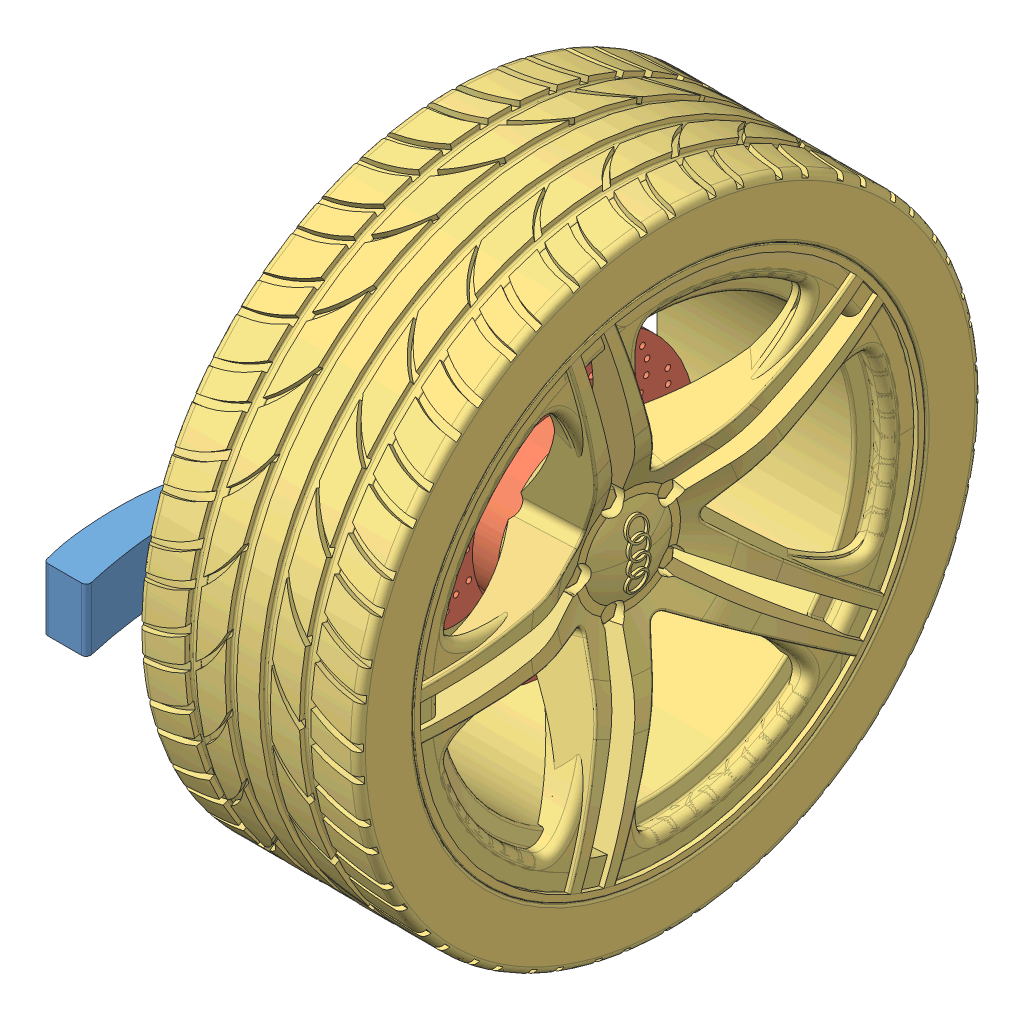
SolidWorks assembly Assem9, configuration Default. Lengths in mm.
Overall size (361.62 668.92 691.48).
3 component instances, 3 part files, 5 mates.
Components (placement in the parent):
- KHUNG TREO R-1: KHUNG TREO R [Default] x (1 0 0) z (0 1 0) size (231.48 449.46 221.1)
- ĐĨA THẮNG-1: ĐĨA THẮNG [Default] at (96.4435 0 0) x (0 -1 0) z (0 0 1) size (303 56.33 303)
- BÁNH XE-1: BÁNH XE [Varsayılan] at (-713.4994 0 0) x (0 -1 0) z (0 0 1) size (668.92 273.92 668.92)
Mates (geometry in assembly coordinates):
- Coincident3: coincident: point of KHUNG TREO R-1
- Concentric1: concentric aligned: cone of KHUNG TREO R-1 through (46.6671 0 0) axis (-1 0 0); cylinder of ĐĨA THẮNG-1 through (96.4435 0 0) axis (-1 0 0) radius 81.625
- Coincident6: coincident aligned: plane of KHUNG TREO R-1 through (140.2735 0 0) normal (1 0 0); plane of ĐĨA THẮNG-1 through (140.2735 35 0) normal (1 0 0)
- Concentric2: concentric anti-aligned: circle of ĐĨA THẮNG-1; circle of BÁNH XE-1
- Coincident7: coincident anti-aligned: plane of ĐĨA THẮNG-1 through (140.2735 35 0) normal (1 0 0); plane of BÁNH XE-1 through (140.2735 0 0) normal (-1 0 0)
